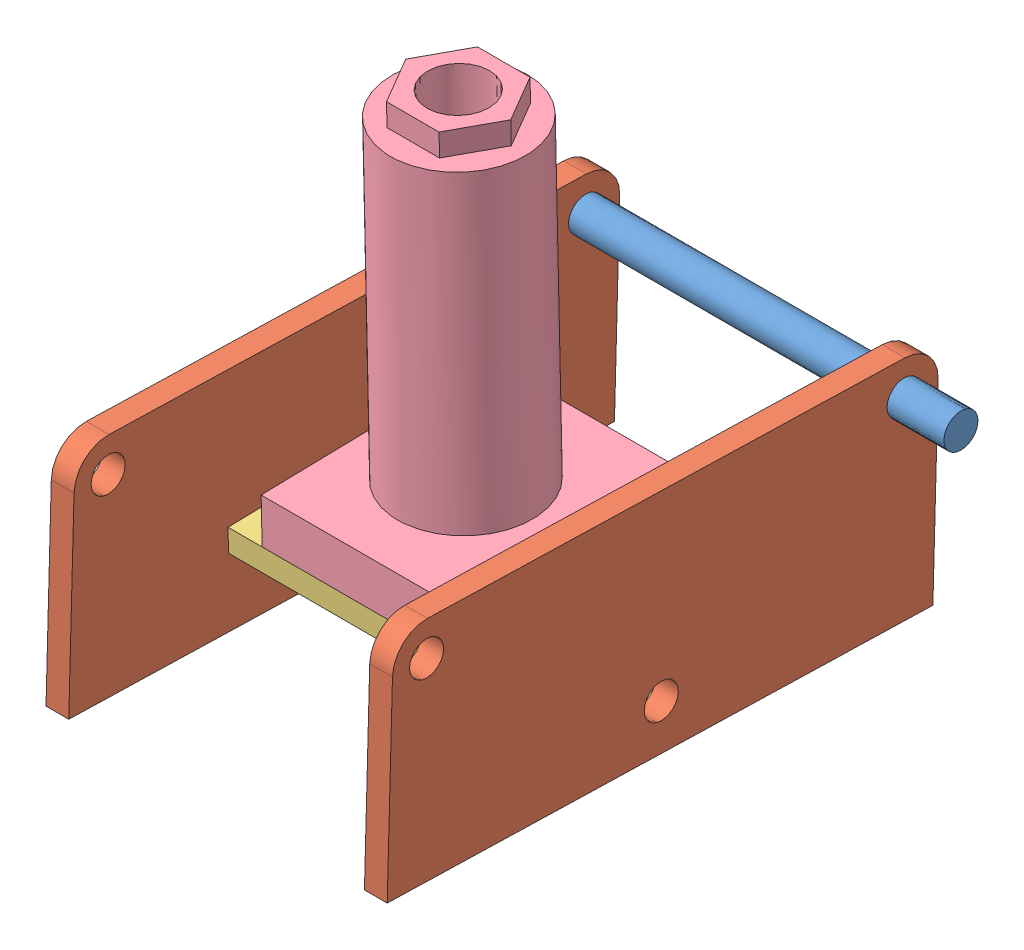
SolidWorks assembly Assem5, configuration Default. Lengths in mm.
Overall size (254 275.37 308.15).
5 component instances, 4 part files, 9 mates.
Components (placement in the parent):
- Jack Pin 1-1: Jack Pin 1 [Default] at (95.1946 133.8204 193.9022) size (254 19.05 19.05)
- Jack Lever-1: Jack Lever [Default] at (184.0946 93.0279 328.4161) x (1 0 0) z (0 0.027303 0.999627) size (12.7 127 304.8)
- Jack Lever-2: Jack Lever [Default] at (6.2946 93.0279 328.4161) x (1 0 0) z (0 0.027303 0.999627) size (12.7 127 304.8)
- Jack Base-1: Jack Base [Default] at (95.1946 77.1616 329.9478) x (1 0 0) z (0 -0.022116 0.999755) size (165.1 44.45 127)
- Jack Body-1: Jack Body [Default] at (95.1946 83.5101 330.0883) x (1 0 0) z (0 -0.022116 0.999755) size (127 215.9 127)
Mates (geometry in assembly coordinates):
- Concentric1: concentric anti-aligned: cylinder of Jack Pin 1-1 through (222.1946 133.8204 193.9022) axis (-1 0 0) radius 9.525; cylinder of Jack Lever-1 through (177.7436 133.8204 193.9022) axis (1 0 0) radius 9.525
- Concentric2: concentric anti-aligned: cylinder of Jack Pin 1-1 through (222.1946 133.8204 193.9022) axis (-1 0 0) radius 9.525; cylinder of Jack Lever-2 through (-0.0564 133.8204 193.9022) axis (1 0 0) radius 9.525
- Concentric3: concentric aligned: cylinder of Jack Lever-1 through (177.7436 54.9421 329.4563) axis (1 0 0) radius 9.525; cylinder of Jack Base-1 through (12.6435 54.9421 329.4563) axis (1 0 0) radius 9.525
- Concentric4: concentric aligned: cylinder of Jack Lever-2 through (-0.0564 54.9421 329.4563) axis (1 0 0) radius 9.525; cylinder of Jack Base-1 through (12.6435 54.9421 329.4563) axis (1 0 0) radius 9.525
- Coincident1: coincident anti-aligned: plane of Jack Lever-2 through (12.6446 93.0279 328.4161) normal (1 0 0); plane of Jack Base-1 through (12.6446 84.9144 266.6038) normal (-1 0 0)
- Coincident2: coincident anti-aligned: plane of Jack Lever-1 through (177.7446 93.0279 328.4161) normal (-1 0 0); plane of Jack Base-1 through (177.7446 84.9144 266.6038) normal (1 0 0)
- Distance1: distance = 31.75 mm aligned: plane of Jack Lever-1 through (190.4446 93.0279 328.4161) normal (1 0 0); plane of Jack Pin 1-1 through (222.1946 133.8204 193.9022) normal (1 0 0)
- Coincident4: coincident anti-aligned: line of Jack Base-1 through (95.1946 84.9144 266.6038) axis (0 -0.022116 0.999755); line of Jack Body-1 through (95.1946 82.1057 393.5727) axis (0 0.022116 -0.999755)
- Coincident5: coincident aligned: line of Jack Base-1 through (12.6446 83.5101 330.0883) axis (1 0 0); line of Jack Body-1 through (31.6946 83.5101 330.0883) axis (1 0 0)
